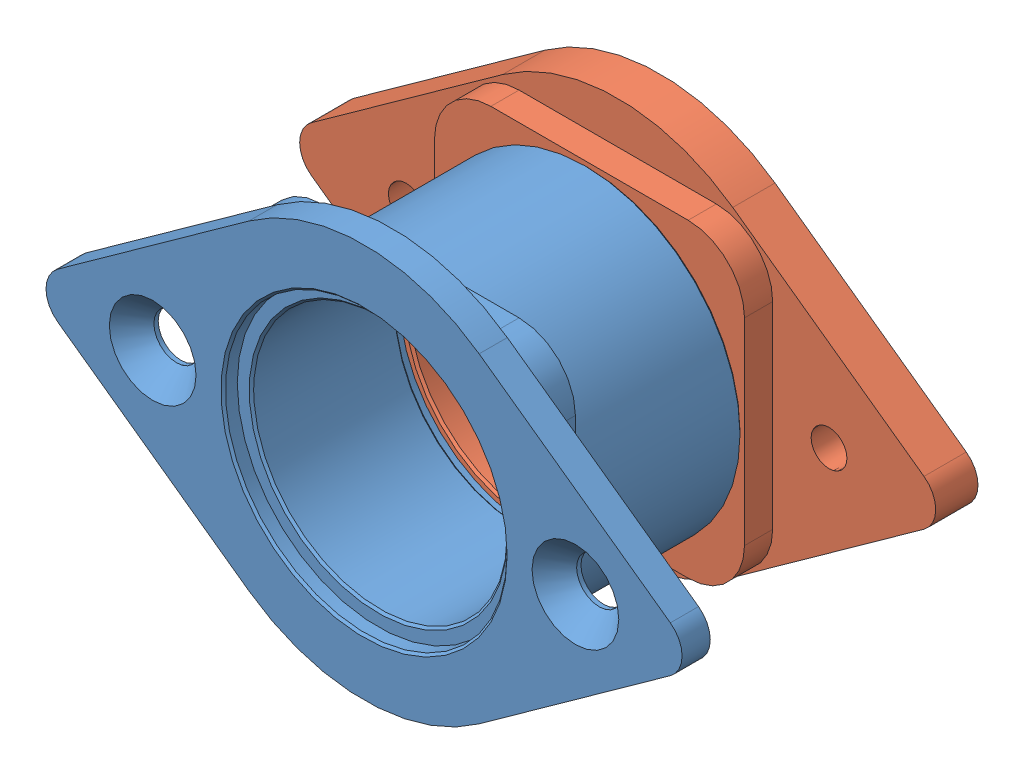
SolidWorks assembly WCP_Side_Bearing_Block_Kit_217-3436 (1)1, configuration Default. Lengths in mm.
Overall size (71.66 44.45 33.34).
2 component instances, 2 part files, 0 mates.
Components (placement in the parent):
- 217-3436-001 Rev2-1: 217-3436-001 Rev2 [Default] at origin size (71.66 44.45 25.15)
- 217-3436-002 Rev2-1: 217-3436-002 Rev2 [Default] at (0 0 -29.3687) x (-1 0 0) z (0 0 -1) size (71.66 44.45 14.29)
